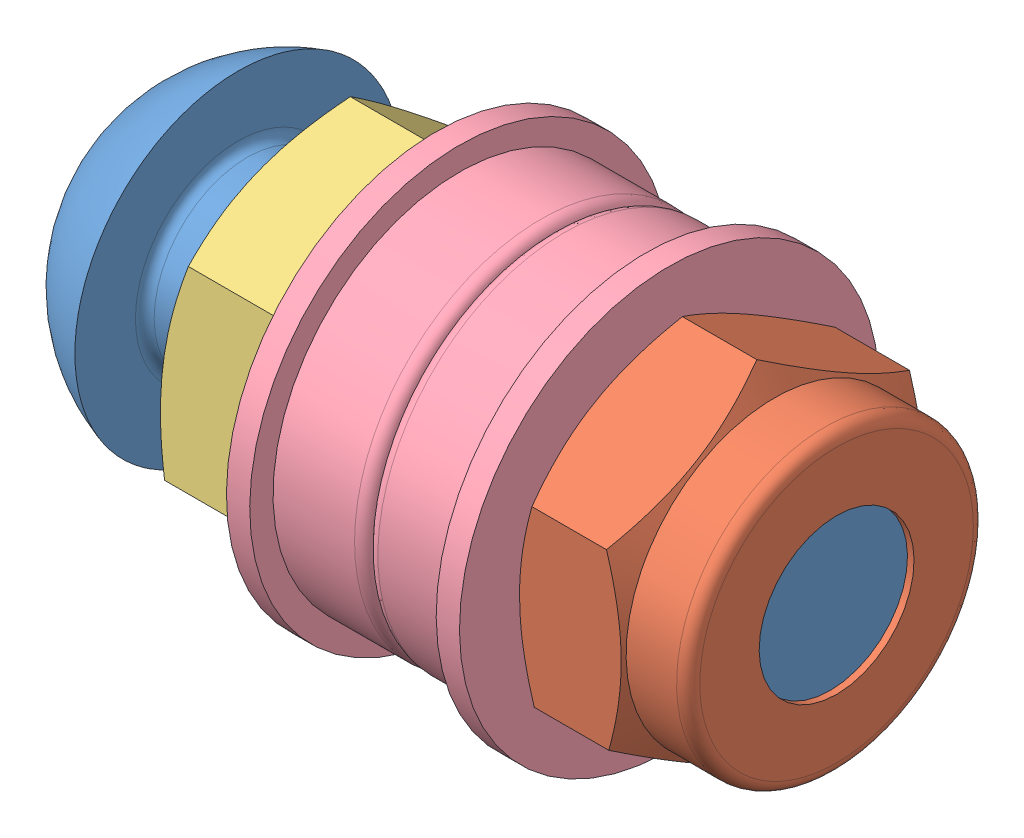
SolidWorks assembly ASM X-Roller Bolt, configuration Standard. Lengths in mm.
Overall size (30.9 25.4 25.4).
5 component instances, 4 part files, 7 mates.
Components (placement in the parent):
- M8X25 Pan Head Screw-1: M8X25 Pan Head Screw [Standard] at origin size (30.62 14.79 14.79)
- M8 Self-locking nut-1: M8 Self-locking nut [Standard] at (27.7325 0 0) x (0 0.488663 0.872473) z (1 0 0) size (15.01 13 7.18)
- M8 nut-1: M8 nut [Standard] at (7.4 0 0) x (0 0.613039 0.790053) z (-1 0 0) size (15.01 13 5.5)
- F688 pillow-1: F688 pillow [Standard] at (22.9 0 0) x (0 0.424513 0.905422) z (0 -0.905422 0.424513) size (18 5 18)
- F688 pillow-2: F688 pillow [Standard] at (12.9 0 0) x (0 0.751639 -0.659574) z (0 -0.659574 -0.751639) size (18 5 18)
Mates (geometry in assembly coordinates):
- Konzentrisch35: concentric: cylinder of M8X25 Pan Head Screw-1 through (14.4 0 0) axis (-1 0 0) radius 4; cylinder of M8 nut-1 through (14.2 0 0) axis (-1 0 0) radius 3.3235
- Konzentrisch36: concentric: cylinder of M8X25 Pan Head Screw-1 through (14.4 0 0) axis (-1 0 0) radius 4; cylinder of F688 pillow-2 through (17.9 0 0) axis (-1 0 0) radius 4
- Konzentrisch37: concentric: cylinder of M8X25 Pan Head Screw-1 through (14.4 0 0) axis (-1 0 0) radius 4; cylinder of F688 pillow-1 through (17.9 0 0) axis (1 0 0) radius 4
- Konzentrisch38: concentric: cylinder of M8X25 Pan Head Screw-1 through (14.4 0 0) axis (-1 0 0) radius 4; cylinder of M8 Self-locking nut-1 through (22.5825 0 0) axis (1 0 0) radius 3.3235
- Deckungsgleich34: coincident: plane of M8 Self-locking nut-1 through (22.9 0.1695 -12.9989) normal (-1 0 0); plane of F688 pillow-1 through (22.9 0 0) normal (1 0 0)
- Deckungsgleich32: coincident: plane of M8 nut-1 through (12.9 -6.1931 -10.6321) normal (1 0 0); plane of F688 pillow-2 through (12.9 0 0) normal (-1 0 0)
- Deckungsgleich33: coincident: plane of F688 pillow-1 through (17.9 0 0) normal (-1 0 0); plane of F688 pillow-2 through (17.9 0 0) normal (1 0 0)
